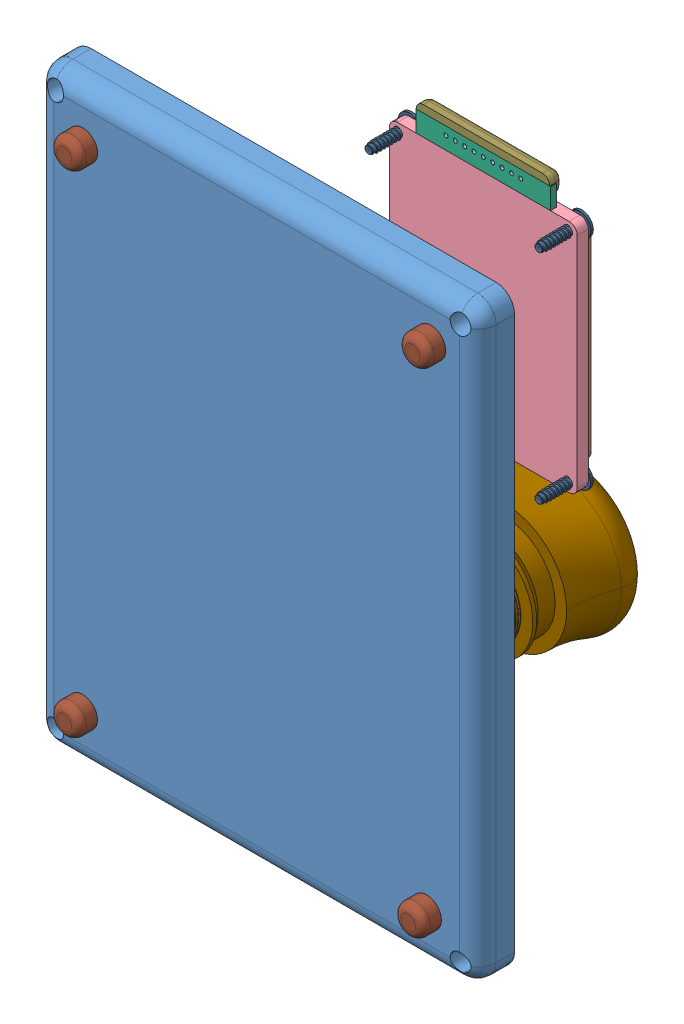
SolidWorks assembly ini, configuration Default. Lengths in mm.
Overall size (120 160 92.06).
20 component instances, 12 part files, 12 mates.
Components (placement in the parent):
- base-1: base [Default] at (30.3532 151.9666 91.7947) size (120 160 10)
- KeyPad_3x4_w_pcb-1: KeyPad_3x4_w_pcb [Default] at (91.866 94.3035 38.7947) x (1 0 0) z (0 0 -1) size (51 69.5 10.29)
  - KeyPad_3x4_w_pcb.step-1: KeyPad_3x4_w_pcb.step [Default] at origin size (51 69.5 10.29)
    - Body_top.step-1: Body_top.step [Default] at origin size (46 56.8 3.6)
    - KeyPad.step-1: KeyPad.step [Default] at origin size (44.02 53.35 7.29)
    - Body_bottom.step-1: Body_bottom.step [Default] at origin size (51 63.8 3)
    - PCB_pads.step-1: PCB_pads.step [Default] at origin size (36.4 5.6 1.61)
    - PCB.step-1: PCB.step [Default] at origin size (36.5 5.7 1.6)
    - PCBtracks.step-1: PCBtracks.step [Default] at origin size (36.45 5.65 1.6)
    - KeyPad_collor.step-1: KeyPad_collor.step [Default] at origin size (40 50 6.89)
- Emergency Stop Button-2: Emergency Stop Button [Default] at (90.3533 26.9639 34.7353) x (0.999972 0.007536 0) z (-0.007536 0.999972 0) size (38.72 65.6 38.72)
- STP310400160-1: STP310400160 [Default] at (68.791 64.7287 37.5551) x (1 0 0) z (0 1 0) size (6.25 12.93 6.25)
- STP310400160-2: STP310400160 [Default] at (114.941 64.7287 37.5551) x (1 0 0) z (0 1 0) size (6.25 12.93 6.25)
- STP310400160-3: STP310400160 [Default] at (68.791 123.8787 37.5551) x (1 0 0) z (0 1 0) size (6.25 12.93 6.25)
- STP310400160-4: STP310400160 [Default] at (114.941 123.8787 37.5551) x (1 0 0) z (0 1 0) size (6.25 12.93 6.25)
- leg-5: leg [Default] at (43.0816 4.9248 106.7947) x (-0.998999 -0.044741 0) z (0 0 -1) size (8 8 5)
- leg-6: leg [Default] at (137.6443 139.0201 106.7947) x (-0.998999 -0.044741 0) z (0 0 -1) size (8 8 5)
- leg-7: leg [Default] at (136.4751 4.5046 106.7947) x (-0.998999 -0.044741 0) z (0 0 -1) size (8 8 5)
- leg-8: leg [Default] at (43.1186 138.1725 106.7947) x (-0.998999 -0.044741 0) z (0 0 -1) size (8 8 5)
- cover-1: cover [Default] at (109.9211 133.9035 40.1947) x (-1 0 0) z (0 0 -1) size (36.3 5.6 3.6)
Mates (geometry in assembly coordinates):
- Coincident50: coincident: plane of KeyPad_3x4_w_pcb-1/KeyPad_3x4_w_pcb.step-1/Body_bottom.step-1 through (91.866 93.5526 38.7947) normal (0 0 -1); plane of STP310400160-1 through (68.791 66.2179 38.7947) normal (0 0 1)
- Coincident51: coincident: plane of KeyPad_3x4_w_pcb-1/KeyPad_3x4_w_pcb.step-1/Body_bottom.step-1 through (91.866 93.5526 38.7947) normal (0 0 -1); plane of STP310400160-2 through (114.941 66.2179 38.7947) normal (0 0 1)
- Coincident52: coincident: plane of KeyPad_3x4_w_pcb-1/KeyPad_3x4_w_pcb.step-1/Body_bottom.step-1 through (91.866 93.5526 38.7947) normal (0 0 -1); plane of STP310400160-3 through (68.791 125.3679 38.7947) normal (0 0 1)
- Coincident53: coincident: plane of KeyPad_3x4_w_pcb-1/KeyPad_3x4_w_pcb.step-1/Body_bottom.step-1 through (91.866 93.5526 38.7947) normal (0 0 -1); plane of STP310400160-4 through (114.941 125.3679 38.7947) normal (0 0 1)
- Concentric11: concentric: circle of KeyPad_3x4_w_pcb-1/KeyPad_3x4_w_pcb.step-1/Body_bottom.step-1; circle of STP310400160-2
- Concentric12: concentric: circle of KeyPad_3x4_w_pcb-1/KeyPad_3x4_w_pcb.step-1/Body_bottom.step-1; circle of STP310400160-4
- Concentric13: concentric: circle of KeyPad_3x4_w_pcb-1/KeyPad_3x4_w_pcb.step-1/Body_bottom.step-1; circle of STP310400160-3
- Coincident60: coincident: plane of base-1 through (30.3532 151.9666 101.7947) normal (0 0 1); plane of leg-5 through (43.0816 4.9248 101.7947) normal (0 0 -1)
- Coincident61: coincident: plane of base-1 through (30.3532 151.9666 101.7947) normal (0 0 1); plane of leg-6 through (137.6443 139.0201 101.7947) normal (0 0 -1)
- Coincident62: coincident: plane of base-1 through (30.3532 151.9666 101.7947) normal (0 0 1); plane of leg-8 through (43.1186 138.1725 101.7947) normal (0 0 -1)
- Coincident63: coincident: plane of base-1 through (30.3532 151.9666 101.7947) normal (0 0 1); plane of leg-7 through (136.4751 4.5046 101.7947) normal (0 0 -1)
- Coincident68: coincident: plane of KeyPad_3x4_w_pcb-1/KeyPad_3x4_w_pcb.step-1/PCB.step-1 through (110.116 131.9035 41.7947) normal (0 1 0); plane of cover-1 through (73.6211 131.9035 41.7947) normal (0 -1 0)
